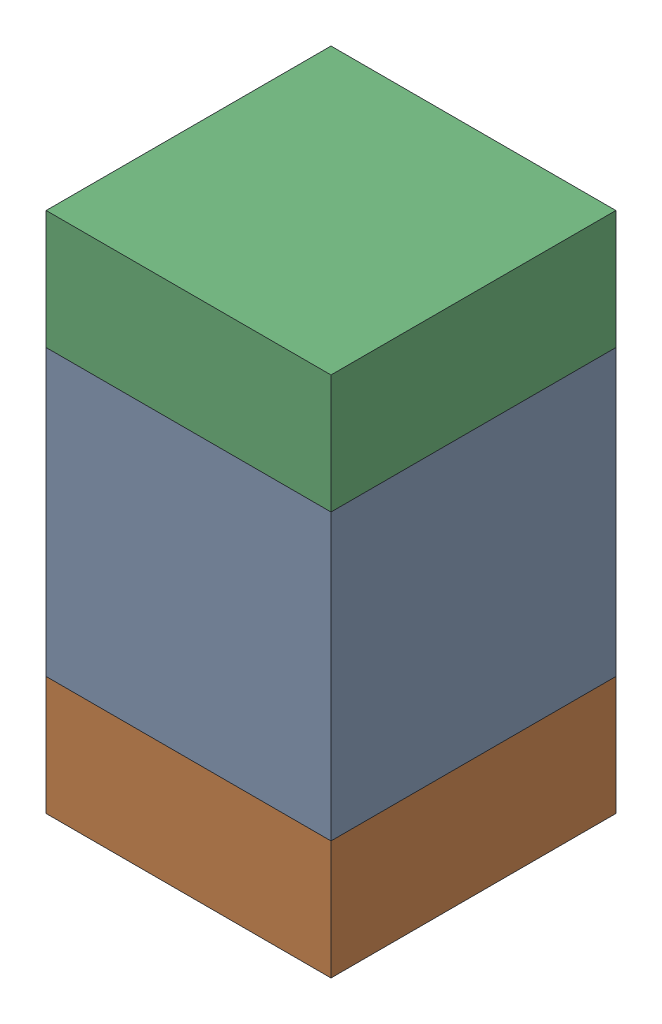
SolidWorks assembly C313_1PCB, configuration Default. Lengths in mm.
Overall size (0.6 1.1 0.6).
6 component instances, 2 part files, 0 mates.
Components (placement in the parent):
- 761606048-1: 761606048 [Default] at (133.4343 111.15 -2.2638) size (0.6 0.6 0.6)
  - Extruded_9-1: Extruded_9 [Default] at origin size (0.6 0.6 0.6)
- 854785296-1: 854785296 [Default] at (133.4343 110.725 -2.2638) size (0.6 0.25 0.6)
  - Extruded_10-1: Extruded_10 [Default] at origin size (0.6 0.25 0.6)
- 854785296-2: 854785296 [Default] at (133.4343 111.575 -2.2638) size (0.6 0.25 0.6)
  - Extruded_10-1: Extruded_10 [Default] at origin size (0.6 0.25 0.6)
